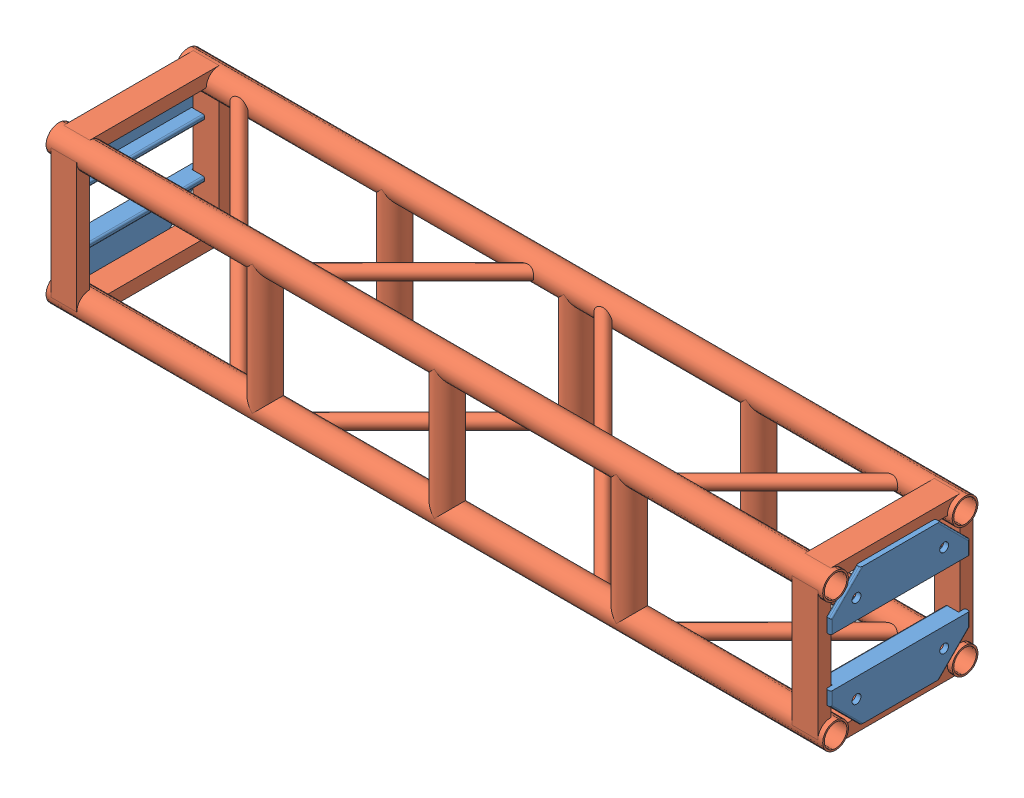
SolidWorks assembly GE-20004, configuration Default. Lengths in mm.
Overall size (1524 304.8 304.8).
5 component instances, 2 part files, 0 mates.
Components (placement in the parent):
- Connection Plate _ TS Standard-3: Connection Plate _ TS Standard [Default] at (-744.5375 -90.7415 0) x (0 0 -1) z (1 0 0) size (273.05 85.72 34.92)
- Connection Plate _ TS Standard-2: Connection Plate _ TS Standard [Default] at (-744.5375 90.7415 0) x (0 0 1) z (1 0 0) size (273.05 85.72 34.92)
- Connection Plate _ TS Standard-4: Connection Plate _ TS Standard [Default] at (744.5375 -90.7415 0) x (0 0 1) z (-1 0 0) size (273.05 85.72 34.92)
- Connection Plate _ TS Standard-5: Connection Plate _ TS Standard [Default] at (744.5375 90.7415 0) x (0 0 -1) z (-1 0 0) size (273.05 85.72 34.92)
- GE-20004 - 01-1: GE-20004 - 01 [Default] at origin size (1524 304.8 304.8)
